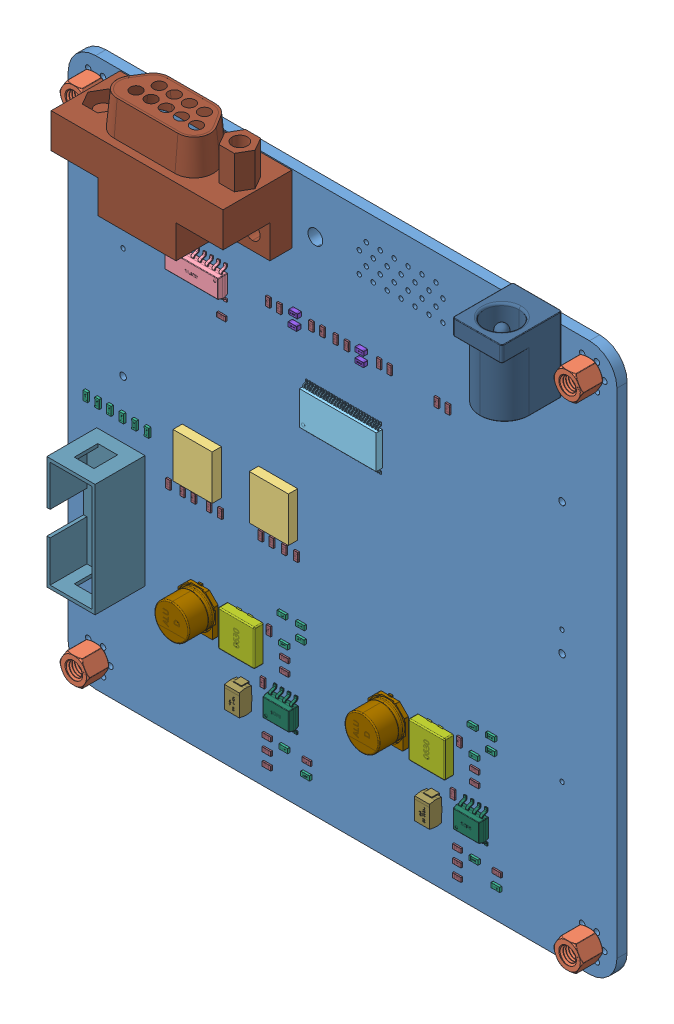
SolidWorks assembly 01_botom, configuration 默认. Lengths in mm.
Overall size (100 105.87 16.35).
80 component instances, 15 part files, 0 mates.
Components (placement in the parent):
- 01_botom_BOARD-1: 01_botom_BOARD [默认] at origin size (100 100 1.87)
- M3x4_N_铜柱大焊盘-1-1: M3x4_N_铜柱大焊盘-1 [默认] at (151.807 43.265 1.8635) size (5.4 5.21 4.07)
- M3x4_N_铜柱大焊盘-1-2: M3x4_N_铜柱大焊盘-1 [默认] at (61.807 43.265 1.8635) size (5.4 5.21 4.07)
- M3x4_N_铜柱大焊盘-1-3: M3x4_N_铜柱大焊盘-1 [默认] at (61.807 133.265 1.8635) size (5.4 5.21 4.07)
- M3x4_N_铜柱大焊盘-1-4: M3x4_N_铜柱大焊盘-1 [默认] at (151.807 133.265 1.8635) size (5.4 5.21 4.07)
- SOT223_L_AMS1117-1-1: SOT223_L_AMS1117-1 [默认] at (95.25 84.328 1.8635) size (7.13 8.13 1.7)
- SOT223_L_AMS1117-1-2: SOT223_L_AMS1117-1 [默认] at (81.349 84.0114 1.8635) size (7.13 8.13 1.7)
- SOP16_MAX232-1-1: SOP16_MAX232-1 [默认] at (85.598 117.267 1.8635) x (0 -1 0) z (0 0 1) size (6.01 10 1.92)
- TSSOP-56_DS90CR287MTDX_NOPB-1-1: TSSOP-56_DS90CR287MTDX_NOPB-1 [默认] at (100.339 98.426 1.8635) x (0 1 0) z (0 0 1) size (8.14 14.08 1.55)
- 0603R_RES-1-1: 0603R_RES-1 [默认] at (64.643 84.709 1.8635) x (0 -1 0) z (0 0 1) size (1.6 0.82 0.45)
- 0603R_RES-1-2: 0603R_RES-1 [默认] at (62.484 84.709 1.8635) x (0 -1 0) z (0 0 1) size (1.6 0.82 0.45)
- 0603R_RES-1-3: 0603R_RES-1 [默认] at (69.215 84.658 1.8635) x (0 -1 0) z (0 0 1) size (1.6 0.82 0.45)
- 0603R_RES-1-4: 0603R_RES-1 [默认] at (71.501 84.658 1.8635) x (0 -1 0) z (0 0 1) size (1.6 0.82 0.45)
- 0603R_RES-1-5: 0603R_RES-1 [默认] at (60.325 84.709 1.8635) x (0 -1 0) z (0 0 1) size (1.6 0.82 0.45)
- 0603R_RES-1-6: 0603R_RES-1 [默认] at (66.929 84.658 1.8635) x (0 -1 0) z (0 0 1) size (1.6 0.82 0.45)
- 0603R_RES-1-7: 0603R_RES-1 [默认] at (133.35 64.77 1.8635) size (1.6 0.82 0.45)
- 0603R_RES-1-8: 0603R_RES-1 [默认] at (130.302 62.484 1.8635) size (1.6 0.82 0.45)
- 0603R_RES-1-9: 0603R_RES-1 [默认] at (134.874 67.056 1.8635) x (-1 0 0) z (0 0 1) size (1.6 0.82 0.45)
- 0603R_RES-1-10: 0603R_RES-1 [默认] at (135.839 43.815 1.8635) x (-1 0 0) z (0 0 1) size (1.6 0.82 0.45)
- 0603R_RES-1-11: 0603R_RES-1 [默认] at (131.864 46.139 1.8635) x (-1 0 0) z (0 0 1) size (1.6 0.82 0.45)
- 0603R_RES-1-12: 0603R_RES-1 [默认] at (131.521 67.056 1.8635) x (-1 0 0) z (0 0 1) size (1.6 0.82 0.45)
- 0603R_RES-1-13: 0603R_RES-1 [默认] at (98.679 65.024 1.8635) size (1.6 0.82 0.45)
- 0603R_RES-1-14: 0603R_RES-1 [默认] at (95.631 62.738 1.8635) size (1.6 0.82 0.45)
- 0603R_RES-1-15: 0603R_RES-1 [默认] at (100.203 67.31 1.8635) x (-1 0 0) z (0 0 1) size (1.6 0.82 0.45)
- 0603R_RES-1-16: 0603R_RES-1 [默认] at (101.168 44.069 1.8635) x (-1 0 0) z (0 0 1) size (1.6 0.82 0.45)
- 0603R_RES-1-17: 0603R_RES-1 [默认] at (97.193 46.393 1.8635) x (-1 0 0) z (0 0 1) size (1.6 0.82 0.45)
- 0603R_RES-1-18: 0603R_RES-1 [默认] at (96.85 67.31 1.8635) x (-1 0 0) z (0 0 1) size (1.6 0.82 0.45)
- L-SMD-0630_L-1-1: L-SMD-0630_L-1 [默认] at (123.698 60.452 1.8635) x (0 1 0) z (0 0 1) size (6.95 6.6 3.03)
- L-SMD-0630_L-1-2: L-SMD-0630_L-1 [默认] at (89.027 60.706 1.8635) x (0 1 0) z (0 0 1) size (6.95 6.6 3.03)
- 0603L_FB-1-1: 0603L_FB-1 [默认] at (111.506 114.554 1.8635) x (-1 0 0) z (0 0 1) size (1.61 0.81 0.81)
- 0603L_FB-1-2: 0603L_FB-1 [默认] at (111.506 116.332 1.8635) x (-1 0 0) z (0 0 1) size (1.61 0.81 0.81)
- 0603L_FB-1-3: 0603L_FB-1 [默认] at (99.314 114.173 1.8635) x (-1 0 0) z (0 0 1) size (1.61 0.81 0.81)
- 0603L_FB-1-4: 0603L_FB-1 [默认] at (99.441 116.205 1.8635) x (-1 0 0) z (0 0 1) size (1.61 0.81 0.81)
- SMD-EC6.3X6.3X10_ECAP-1-1: SMD-EC6.3X6.3X10_ECAP-1 [默认] at (115.6966 63.3408 1.8635) x (0 -1 0) z (0 0 1) size (7 6.6 5.4)
- SMD-EC6.3X6.3X10_ECAP-1-2: SMD-EC6.3X6.3X10_ECAP-1 [默认] at (81.0256 63.5948 1.8635) x (0 -1 0) z (0 0 1) size (7 6.6 5.4)
- DC-005_DC_Socket-1-1: DC-005_DC_Socket-1 [默认] at (142.494 127.023 1.8635) x (0 1 0) z (0 0 1) size (14.15 9.3 15)
- DB9_F_90_DB9_F-1-1: DB9_F_90_DB9_F-1 [默认] at (76.4032 127.508 1.8635) x (-1 0 0) z (0 0 1) size (31.31 18.4 12.55)
- SMA_DO-214AC_DIODE-1-1: SMA_DO-214AC_DIODE-1 [默认] at (123.698 48.514 1.8635) x (0 1 0) z (0 0 1) size (4.6 2.7 2.4)
- SMA_DO-214AC_DIODE-1-2: SMA_DO-214AC_DIODE-1 [默认] at (89.027 48.768 1.8635) x (0 1 0) z (0 0 1) size (4.6 2.7 2.4)
- 0603C_CAP-1-1: 0603C_CAP-1 [默认] at (75.2766 76.7026 1.8635) x (0 1 0) z (0 0 1) size (1.6 0.8 0.3)
- 0603C_CAP-1-2: 0603C_CAP-1 [默认] at (92.075 76.962 1.8635) x (0 1 0) z (0 0 1) size (1.6 0.8 0.3)
- 0603C_CAP-1-3: 0603C_CAP-1 [默认] at (94.098 76.9566 1.8635) x (0 1 0) z (0 0 1) size (1.6 0.8 0.3)
- 0603C_CAP-1-4: 0603C_CAP-1 [默认] at (96.384 76.9566 1.8635) x (0 1 0) z (0 0 1) size (1.6 0.8 0.3)
- 0603C_CAP-1-5: 0603C_CAP-1 [默认] at (98.552 76.962 1.8635) x (0 1 0) z (0 0 1) size (1.6 0.8 0.3)
- 0603C_CAP-1-6: 0603C_CAP-1 [默认] at (135.8954 46.0666 1.8635) x (-1 0 0) z (0 0 1) size (1.6 0.8 0.3)
- 0603C_CAP-1-7: 0603C_CAP-1 [默认] at (130.2966 58.0734 1.8635) size (1.6 0.8 0.3)
- 0603C_CAP-1-8: 0603C_CAP-1 [默认] at (130.2966 60.207 1.8635) size (1.6 0.8 0.3)
- 0603C_CAP-1-9: 0603C_CAP-1 [默认] at (127.1216 46.2624 1.8635) size (1.6 0.8 0.3)
- 0603C_CAP-1-10: 0603C_CAP-1 [默认] at (127.1216 43.9764 1.8635) size (1.6 0.8 0.3)
- 0603C_CAP-1-11: 0603C_CAP-1 [默认] at (127.1216 41.6904 1.8635) size (1.6 0.8 0.3)
- 0603C_CAP-1-12: 0603C_CAP-1 [默认] at (128.2673 62.5104 1.8635) x (0 1 0) z (0 0 1) size (1.6 0.8 0.3)
- 0603C_CAP-1-13: 0603C_CAP-1 [默认] at (127.118 53.7156 1.8635) x (0 1 0) z (0 0 1) size (1.6 0.8 0.3)
- 0603C_CAP-1-14: 0603C_CAP-1 [默认] at (79.874 76.8296 1.8635) x (0 1 0) z (0 0 1) size (1.6 0.8 0.3)
- 0603C_CAP-1-15: 0603C_CAP-1 [默认] at (77.842 76.8296 1.8635) x (0 1 0) z (0 0 1) size (1.6 0.8 0.3)
- 0603C_CAP-1-16: 0603C_CAP-1 [默认] at (82.668 76.8296 1.8635) x (0 1 0) z (0 0 1) size (1.6 0.8 0.3)
- 0603C_CAP-1-17: 0603C_CAP-1 [默认] at (84.7 76.8296 1.8635) x (0 1 0) z (0 0 1) size (1.6 0.8 0.3)
- 0603C_CAP-1-18: 0603C_CAP-1 [默认] at (101.2244 46.3206 1.8635) x (-1 0 0) z (0 0 1) size (1.6 0.8 0.3)
- 0603C_CAP-1-19: 0603C_CAP-1 [默认] at (95.6256 58.3274 1.8635) size (1.6 0.8 0.3)
- 0603C_CAP-1-20: 0603C_CAP-1 [默认] at (95.6256 60.461 1.8635) size (1.6 0.8 0.3)
- 0603C_CAP-1-21: 0603C_CAP-1 [默认] at (92.4506 46.5164 1.8635) size (1.6 0.8 0.3)
- 0603C_CAP-1-22: 0603C_CAP-1 [默认] at (92.4506 44.2304 1.8635) size (1.6 0.8 0.3)
- 0603C_CAP-1-23: 0603C_CAP-1 [默认] at (92.4506 41.9444 1.8635) size (1.6 0.8 0.3)
- 0603C_CAP-1-24: 0603C_CAP-1 [默认] at (93.5964 62.7643 1.8635) x (0 1 0) z (0 0 1) size (1.6 0.8 0.3)
- 0603C_CAP-1-25: 0603C_CAP-1 [默认] at (92.447 53.9696 1.8635) x (0 1 0) z (0 0 1) size (1.6 0.8 0.3)
- 0603C_CAP-1-26: 0603C_CAP-1 [默认] at (80.3856 121.929 1.8635) size (1.6 0.8 0.3)
- 0603C_CAP-1-27: 0603C_CAP-1 [默认] at (84.1956 108.721 1.8635) size (1.6 0.8 0.3)
- 0603C_CAP-1-28: 0603C_CAP-1 [默认] at (83.6876 120.1764 1.8635) size (1.6 0.8 0.3)
- 0603C_CAP-1-29: 0603C_CAP-1 [默认] at (105.731 114.8026 1.8635) x (0 1 0) z (0 0 1) size (1.6 0.8 0.3)
- 0603C_CAP-1-30: 0603C_CAP-1 [默认] at (107.763 114.8026 1.8635) x (0 1 0) z (0 0 1) size (1.6 0.8 0.3)
- 0603C_CAP-1-31: 0603C_CAP-1 [默认] at (113.656 114.9296 1.8635) x (0 1 0) z (0 0 1) size (1.6 0.8 0.3)
- 0603C_CAP-1-32: 0603C_CAP-1 [默认] at (115.561 114.9296 1.8635) x (0 1 0) z (0 0 1) size (1.6 0.8 0.3)
- 0603C_CAP-1-33: 0603C_CAP-1 [默认] at (93.4374 114.5486 1.8635) x (0 1 0) z (0 0 1) size (1.6 0.8 0.3)
- 0603C_CAP-1-34: 0603C_CAP-1 [默认] at (95.4694 114.5486 1.8635) x (0 1 0) z (0 0 1) size (1.6 0.8 0.3)
- 0603C_CAP-1-35: 0603C_CAP-1 [默认] at (101.3116 114.6756 1.8635) x (0 1 0) z (0 0 1) size (1.6 0.8 0.3)
- 0603C_CAP-1-36: 0603C_CAP-1 [默认] at (103.3436 114.8026 1.8635) x (0 1 0) z (0 0 1) size (1.6 0.8 0.3)
- 0603C_CAP-1-37: 0603C_CAP-1 [默认] at (126.1781 114.0406 1.8635) x (0 1 0) z (0 0 1) size (1.6 0.8 0.3)
- 0603C_CAP-1-38: 0603C_CAP-1 [默认] at (124.1716 114.0406 1.8635) x (0 1 0) z (0 0 1) size (1.6 0.8 0.3)
- JTAG_JTAG-1-1: JTAG_JTAG-1 [默认] at (66.421 69.342 1.8635) x (0 -1 0) z (0 0 1) size (20.6 8.8 9.1)
- SOIC-8_TPS54331DR-1-1: SOIC-8_TPS54331DR-1 [默认] at (131.191 52.324 1.8635) x (0 1 0) z (0 0 1) size (6.01 5 1.9)
- SOIC-8_TPS54331DR-1-2: SOIC-8_TPS54331DR-1 [默认] at (96.52 52.578 1.8635) x (0 1 0) z (0 0 1) size (6.01 5 1.9)
